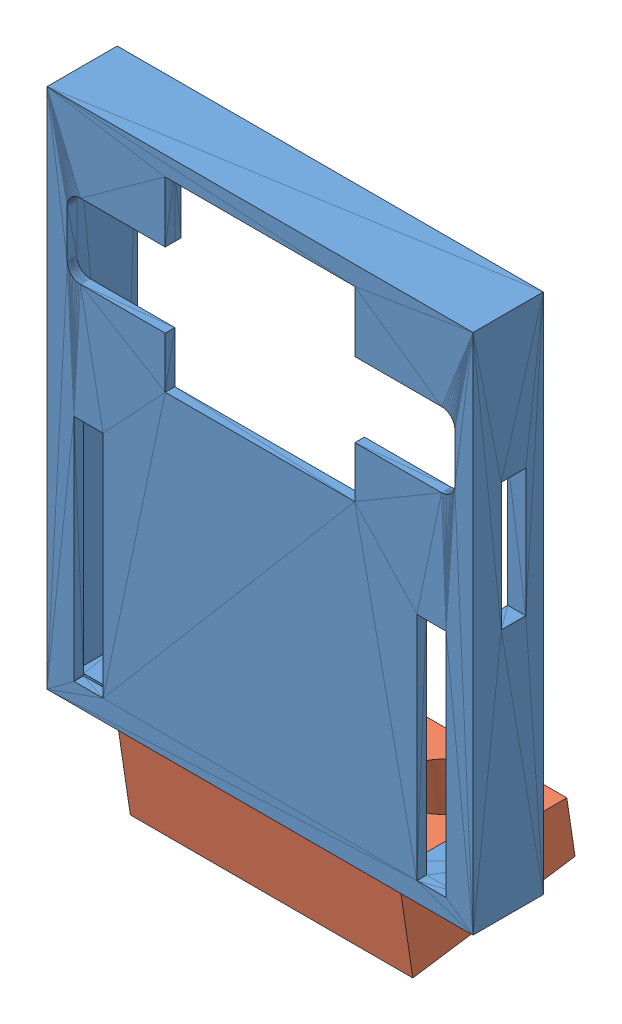
SolidWorks assembly OpenMV_Enclosure, configuration Default. Lengths in mm.
Overall size (40 56.42 16.34).
2 component instances, 2 part files, 2 mates.
Components (placement in the parent):
- OpenMV_rev_6_Camera_Top_cover-1: OpenMV_rev_6_Camera_Top_cover [Default] at (-94.2467 -46.7915 52.4598) x (-1 0 0) z (0 0 -1) size (40 49 6.6)
- OpenMV_Mount_FromPIR-2: OpenMV_Mount_FromPIR [Default] at (4.8918 -15.7749 40.6192) x (0 0.98903 0.147712) z (1 0 0) size (7.5 15.4 26.52)
Mates (geometry in assembly coordinates):
- Coincident5: coincident anti-aligned: plane of OpenMV_rev_6_Camera_Top_cover-1 through (-94.2467 3.7085 52.4598) normal (0 -1 0); plane of OpenMV_Mount_FromPIR-2 through (-30.5282 3.7085 35.0359) normal (0 1 0)
- Coincident6: coincident anti-aligned: line of OpenMV_rev_6_Camera_Top_cover-1 through (25.7532 3.7085 50.6067) axis (-1 0 0); line of OpenMV_Mount_FromPIR-2 through (-7.5282 3.7085 50.6067) axis (1 0 0)
